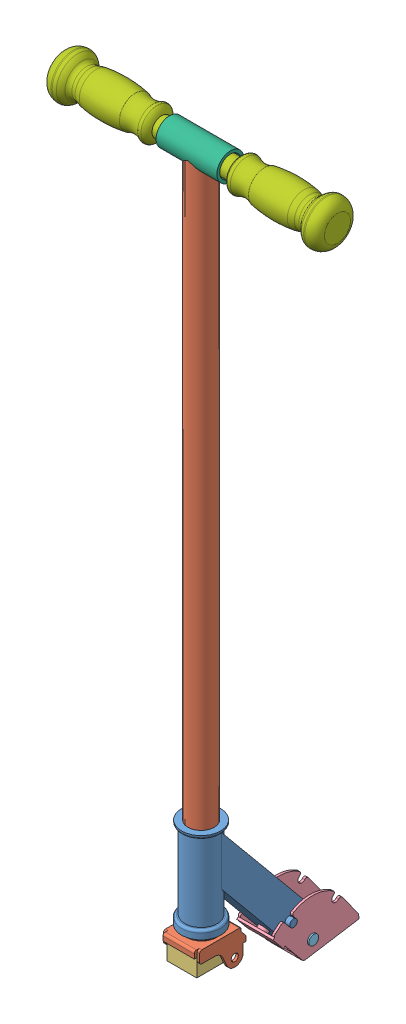
SolidWorks assembly Steering Assembly, configuration Default. Lengths in mm.
Overall size (309.88 860.55 184.46).
8 component instances, 7 part files, 18 mates.
Components (placement in the parent):
- Steering Tube-1: Steering Tube [Default] at (-46.6628 1.0524 23.9083) size (46 172.6 138.23)
- Steering Fork-1: Steering Fork [Default] at (-46.6628 -7.0629 23.9083) size (40.83 796.55 55.73)
- Steering Rubber-1: Steering Rubber [Default] at (-29.0415 -31.7009 46.4508) x (-1 0 0) z (0 0 -1) size (33.35 24.64 40.64)
- Steering Plate-1: Steering Plate [Default] at (-46.8533 -67.8731 -102.6663) x (1 0 0) z (0 -0.157552 0.987511) size (40.72 57.11 91.68)
- Steering Pin-1: Steering Pin [Default] at (-47.4883 -56.2367 -81.2488) size (45.34 11 11)
- Steering Tube Split-1: Steering Tube Split [Default] at (-82.2228 756.7024 23.9083) x (0 0 1) z (0 1 0) size (30.48 68.58 30.48)
- Handlebar-1: Handlebar [Default] at (-45.3928 756.7024 23.9083) x (0 -0.997722 -0.067462) z (-1 0 0) size (49.81 49.81 152.4)
- Handlebar-2: Handlebar [Default] at (-50.4728 756.7024 23.9083) x (0 0 -1) z (1 0 0) size (49.81 49.81 152.4)
Mates (geometry in assembly coordinates):
- Concentric1: concentric anti-aligned: cylinder of Steering Tube-1 through (-46.6628 102.6524 23.9083) axis (0 1 0) radius 18.3134; cylinder of Steering Fork-1 through (-46.6628 756.7024 23.9083) axis (0 -1 0) radius 14.8209
- Coincident1: coincident anti-aligned: plane of Steering Tube-1 through (-46.6628 1.0524 23.9083) normal (0 -1 0); plane of Steering Fork-1 through (-46.6633 1.0524 23.3495) normal (0 1 0)
- Coincident2: coincident anti-aligned: plane of Steering Fork-1 through (-29.0632 -7.0629 1.3489) normal (0 -1 0); plane of Steering Rubber-1 through (-62.4091 -7.0629 5.826) normal (0 1 0)
- Coincident3: coincident anti-aligned: plane of Steering Rubber-1 through (-62.3701 -7.0629 46.4659) normal (0.000961 0 1); plane of Steering Fork-1 through (-64.2624 -11.8889 46.4678) normal (-0.000961 0 -1)
- Coincident4: coincident anti-aligned: plane of Steering Fork-1 through (-29.0227 -6.8089 43.4621) normal (-1 0 0.000961); plane of Steering Rubber-1 through (-29.0589 -34.2726 5.7939) normal (1 0 -0.000961)
- Concentric4: concentric anti-aligned: cylinder of Steering Pin-1 through (-24.8188 -56.2367 -81.2488) axis (1 0 0) radius 3.937; cylinder of Steering Tube-1 through (-29.0733 -56.2367 -81.2488) axis (-1 0 0) radius 3.9688
- Concentric5: concentric anti-aligned: cylinder of Steering Pin-1 through (-24.8188 -56.2367 -81.2488) axis (1 0 0) radius 3.937; cylinder of Steering Plate-1 through (-26.4952 -56.2367 -81.2488) axis (-1 0 0) radius 4.0704
- Coincident5: coincident anti-aligned: plane of Steering Plate-1 through (-26.4952 -70.1385 -72.345) normal (1 0 0); plane of Steering Pin-1 through (-26.4952 -56.2367 -77.3118) normal (-1 0 0)
- Coincident6: coincident anti-aligned: plane of Steering Tube-1 through (-29.0733 -102.6765 33.6325) normal (1 0 0); plane of Steering Plate-1 through (-29.0733 -70.1385 -72.345) normal (-1 0 0)
- Coincident7: coincident: cylinder of Steering Tube-1 through (-23.6631 -27.3112 -57.2987) axis (-1 0 0) radius 4.1974; line of Steering Plate-1 through (-26.4952 -29.5461 -53.7458) axis (-1 0 0)
- Concentric6: concentric anti-aligned: cylinder of Steering Fork-1 through (-46.6628 756.7024 23.9083) axis (0 -1 0) radius 14.8209; cylinder of Steering Tube Split-1 through (-46.6628 688.1224 23.9083) axis (0 1 0) radius 14.605
- Coincident8: coincident anti-aligned: plane of Steering Fork-1 through (-46.6628 756.7024 23.9083) normal (0 1 0); plane of Steering Tube Split-1 through (-46.6628 756.7024 23.9083) normal (0 -1 0)
- Concentric7: concentric aligned: cylinder of Steering Tube Split-1 through (-82.2228 756.7024 23.9425) axis (1 0 -0.000961) radius 12.065; circle of Handlebar-1
- Parallel1: parallel anti-aligned: plane of Steering Fork-1 through (-26.2287 -6.8089 43.4594) normal (1 0 -0.000961); plane of Steering Tube Split-1 through (-82.2228 756.7024 23.9425) normal (-1 0 0.000961)
- Distance1: distance = 120.65 mm aligned: plane of Steering Tube Split-1 through (-13.6428 756.7024 23.9083) normal (1 0 0); plane of Handlebar-1 through (107.0072 756.7024 23.9083) normal (1 0 0)
- Concentric8: concentric aligned: cylinder of Steering Tube Split-1 through (-13.6428 756.7024 23.8766) axis (-1 0 0.000961) radius 15.24; circle of Handlebar-2
- Distance2: distance = 120.65 mm aligned: plane of Handlebar-2 through (-202.8728 756.7024 23.9083) normal (-1 0 0); plane of Steering Tube Split-1 through (-82.2228 756.7024 23.9083) normal (-1 0 0)
- Parallel2: parallel aligned: plane of Steering Fork-1 through (-67.078 -6.8089 43.479) normal (-1 0 0); plane of Steering Plate-1 through (-67.2114 -70.1385 -72.345) normal (-1 0 0)
